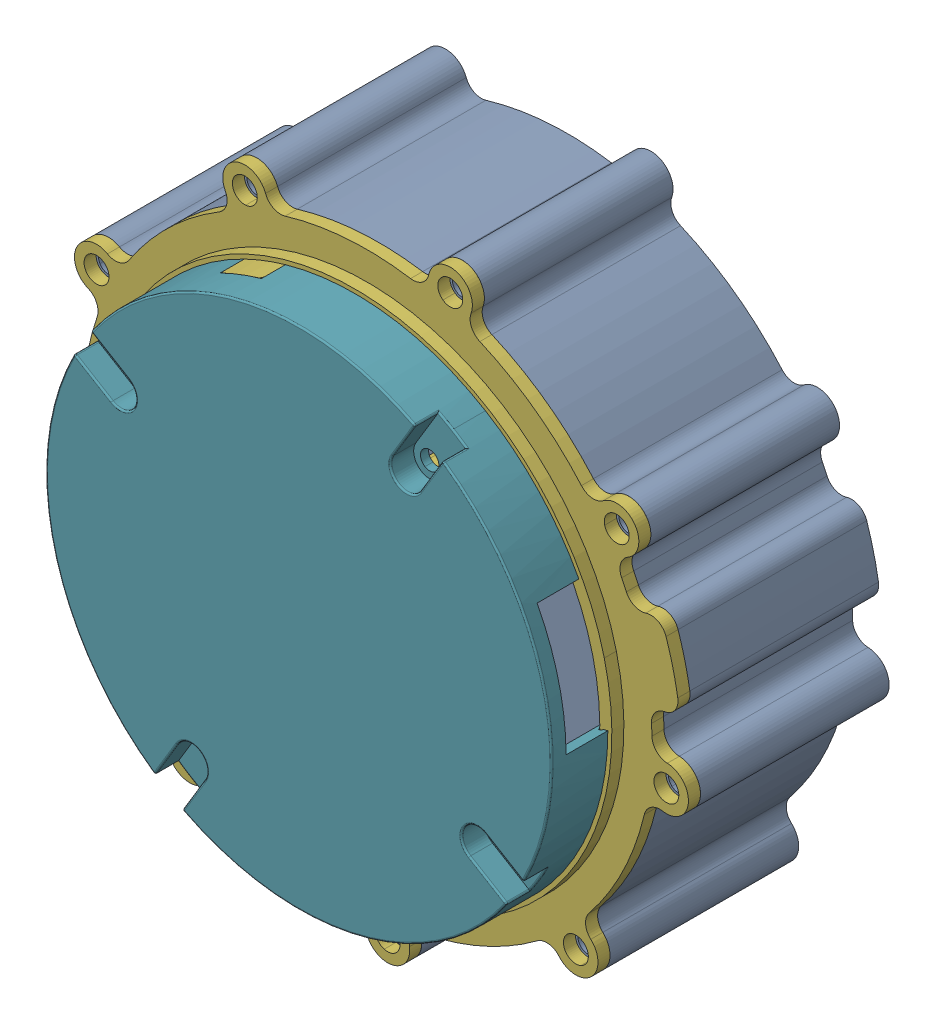
SolidWorks assembly 3_1_02_067_0003_ASM_1_ASM_1_ASM_ASM.stp, configuration 默认. Lengths in mm.
Overall size (96.28 96.17 36.5).
7 component instances, 7 part files, 0 mates.
Components (placement in the parent):
- 1_1_06_EB673-504_1_1_1_1_1.stp-1: 1_1_06_EB673-504_1_1_1_1_1.stp [默认] at (39.8324 39.833 -22) size (79.19 78.95 25.5)
- 1_2_04_670601_1_1_1_1_1.stp-1: 1_2_04_670601_1_1_1_1_1.stp [默认] at (93.9161 79.9966 -44) size (37 37 4)
- 1_1_02_EB671-500_1_1_1_1_1.stp-1: 1_1_02_EB671-500_1_1_1_1_1.stp [默认] at (93.9161 79.9966 -44.4) x (-0.960973 0.276644 0) z (0 0 1) size (33 33 8.5)
- 1_2_04_694000_1_1_1_1_1.stp-1: 1_2_04_694000_1_1_1_1_1.stp [默认] at (93.9161 79.9966 -44.5) size (11 11 4)
- 1_2_06_000213_1_1_1_1_1.stp-1: 1_2_06_000213_1_1_1_1_1.stp [默认] at (93.9161 79.9966 -45.5) size (38.8 36.2 1.5)
- 1_1_31_QT-642_1_1_1_1_1.stp-1: 1_1_31_QT-642_1_1_1_1_1.stp [默认] at (93.9161 79.9966 -22) x (-0.970555 -0.24088 0) z (0 0 -1) size (79.5 79.36 6)
- 1_1_06_EB673-502_1_1_1_1_1.stp-1: 1_1_06_EB673-502_1_1_1_1_1.stp [默认] at (93.9161 79.9966 -13) x (-0.515958 -0.856614 0) z (0 0 -1) size (63 63 8)
